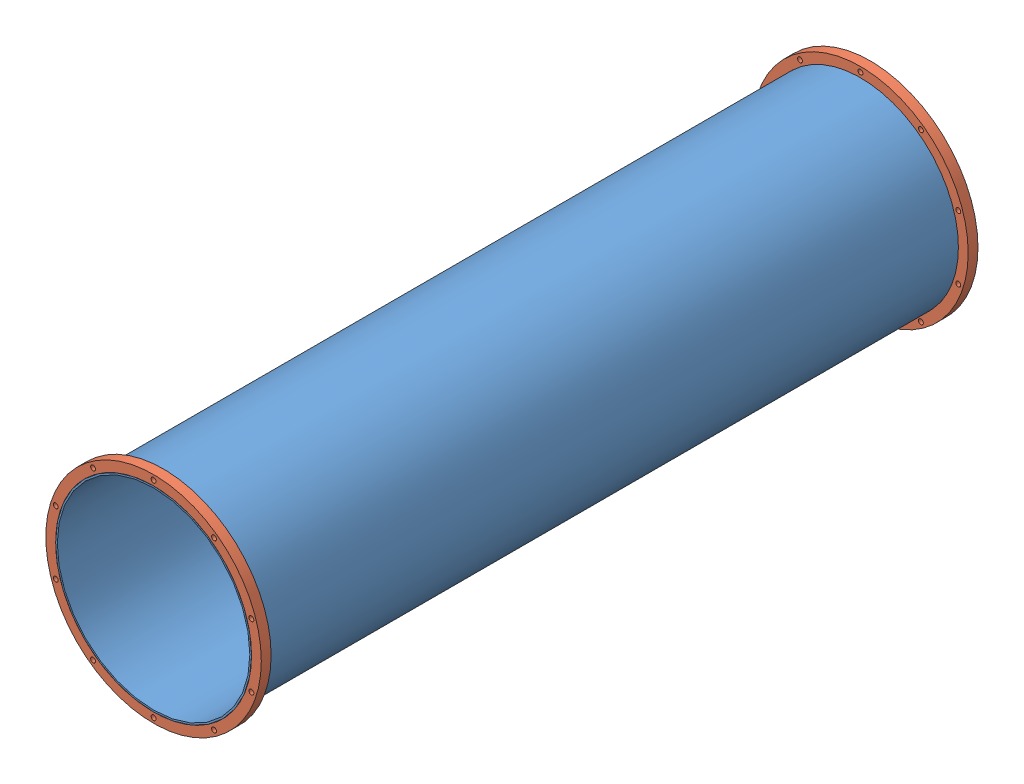
SolidWorks assembly Сборка2, configuration Default. Lengths in mm.
Overall size (257.4 257.4 856).
3 component instances, 2 part files, 3 mates.
Components (placement in the parent):
- Обічайка1-1: Обічайка1 [По умолчанию] at (892.2668 99.0076 678.5911) size (234 234 856)
- флянець-1: флянець [По умолчанию] at (892.2668 99.0076 678.5911) size (257.4 257.4 11.7)
- флянець-2: флянець [По умолчанию] at (892.2668 99.0076 -165.7089) size (257.4 257.4 11.7)
Mates (geometry in assembly coordinates):
- Концентричный2: concentric aligned: circle of флянець-1; circle of Обічайка1-1
- Совпадение1: coincident aligned: circle of Обічайка1-1; circle of флянець-1
- Совпадение2: coincident aligned: circle of Обічайка1-1; circle of флянець-2
